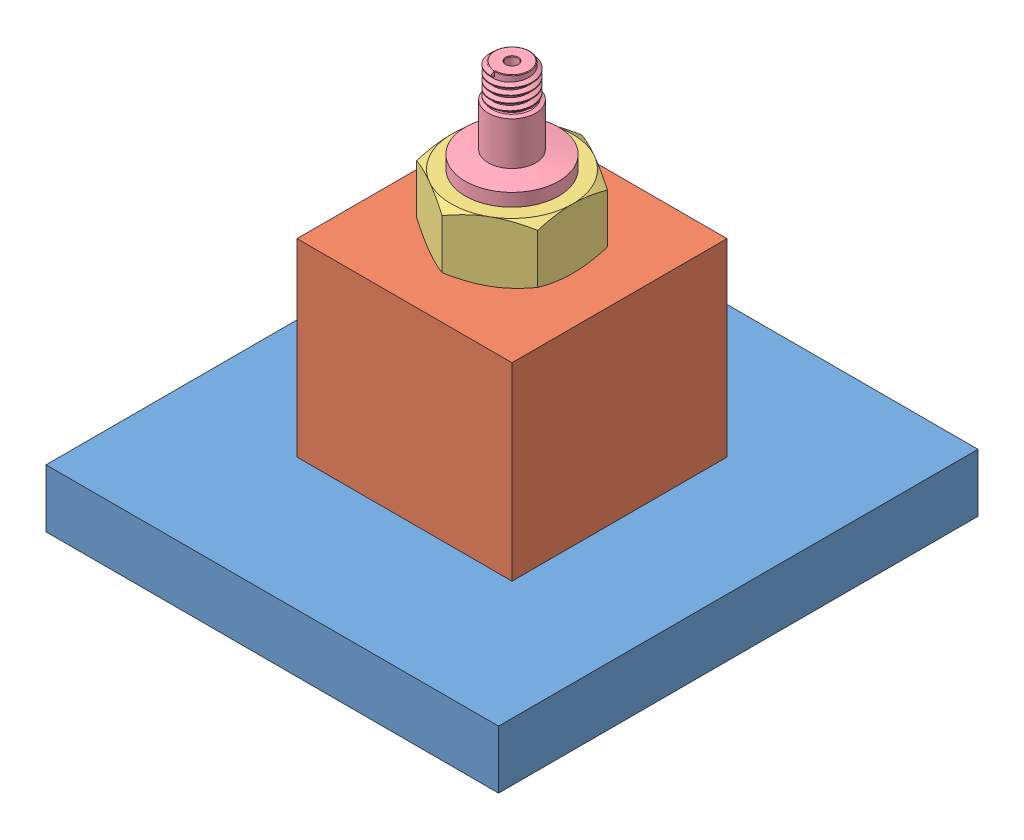
SolidWorks assembly Pressure_Transducer_Asm, configuration Default. Lengths in mm.
Overall size (53.47 47.4 56.64).
4 component instances, 4 part files, 8 mates.
Components (placement in the parent):
- Pressure_Transducer_Base-1: Pressure_Transducer_Base [Default] at (-6.6385 -12.452 9.7108) size (53.47 6.86 56.64)
- Pressure_Transducer_Cube_Housing-1: Pressure_Transducer_Cube_Housing [Default] at (-6.6385 -5.594 9.7108) size (25.4 22.35 25.4)
- Pressure_Transducer_Hex_Nut-1: Pressure_Transducer_Hex_Nut [92680A610] at (-6.6385 20.314 9.7108) size (14.29 8.22 16.5)
- Pressure_Transducer_SMA-2: Pressure_Transducer_SMA [Default] at (-6.6385 23.87 9.7108) x (0 0 -1) z (1 0 0) size (13.23 11.07 12.35)
Mates (geometry in assembly coordinates):
- Coincident1: coincident aligned: circle of Pressure_Transducer_Base-1; circle of Pressure_Transducer_Cube_Housing-1
- Parallel1: parallel aligned: line of Pressure_Transducer_Base-1 through (-33.372 -5.594 38.0318) axis (1 0 0); line of Pressure_Transducer_Cube_Housing-1 through (-19.3385 -5.594 22.4108) axis (1 0 0)
- Concentric1: concentric aligned: circle of Pressure_Transducer_Cube_Housing-1; circle of Pressure_Transducer_Hex_Nut-1
- Coincident3: coincident anti-aligned: plane of Pressure_Transducer_Cube_Housing-1 through (-6.6385 16.758 9.7108) normal (0 1 0); plane of Pressure_Transducer_Hex_Nut-1 through (-13.7822 16.758 5.5863) normal (0 -1 0)
- Parallel2: parallel aligned: plane of Pressure_Transducer_Cube_Housing-1 through (6.0615 16.758 22.4108) normal (1 0 0); plane of Pressure_Transducer_Hex_Nut-1 through (0.5053 23.87 13.8352) normal (1 0 0)
- Concentric2: concentric: circle of Pressure_Transducer_Hex_Nut-1; circle of Pressure_Transducer_SMA-2
- Coincident5: coincident: plane of Pressure_Transducer_Hex_Nut-1 through (-13.7822 23.87 5.5863) normal (0 1 0); plane of Pressure_Transducer_SMA-2 through (-6.6385 23.87 9.7108) normal (0 -1 0)
- Parallel3: parallel aligned: plane of Pressure_Transducer_Hex_Nut-1 through (0.5053 23.87 13.8352) normal (1 0 0); plane of Pressure_Transducer_SMA-2 through (-6.6385 34.6467 12.2359) normal (1 0 0)
